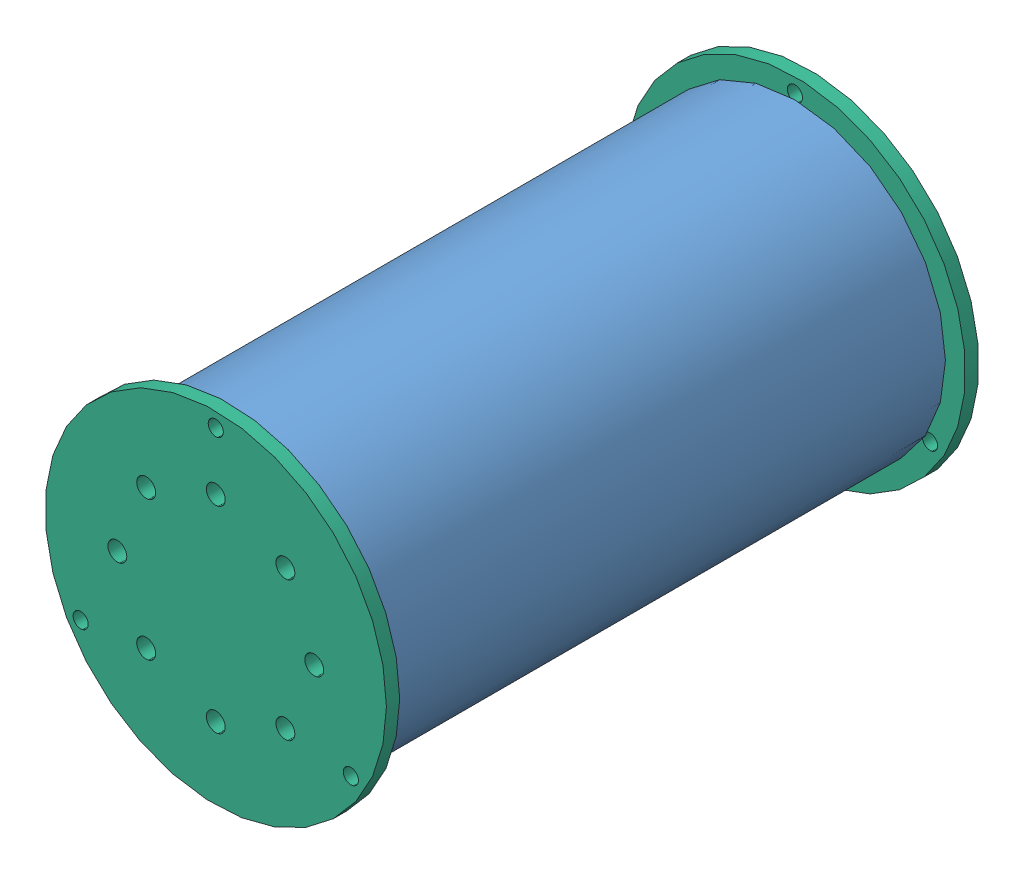
SolidWorks assembly enclosure, configuration Default. Lengths in mm.
Overall size (180 180 327.78).
19 component instances, 6 part files, 13 mates.
Components (placement in the parent):
- tube-1: tube [Default] at origin size (158.75 158.75 298.45)
- board-1: board [Default] at origin size (101.6 76.2 3.81)
- connector-1: connector [Default] at (31.7768 -36.068 -5.2832) x (-1 0 0) z (0 -1 0) size (69.85 16.51 23.62)
- receptical-1: receptical [Default] at (-29.8182 -39.624 0.127) x (1 0 0) z (0 1 0) size (69.85 11.94 21.72)
- backplane-1: backplane [Default] at (1.4763 -54.324 122.6722) x (0 0 1) z (-1 0 0) size (290 2 80)
- receptical-6: receptical [Default] at (-29.8182 -39.624 60.127) x (1 0 0) z (0 1 0) size (69.85 11.94 21.72)
- receptical-7: receptical [Default] at (-29.8182 -39.624 120.127) x (1 0 0) z (0 1 0) size (69.85 11.94 21.72)
- receptical-8: receptical [Default] at (-29.8182 -39.624 180.127) x (1 0 0) z (0 1 0) size (69.85 11.94 21.72)
- receptical-9: receptical [Default] at (-29.8182 -39.624 240.127) x (1 0 0) z (0 1 0) size (69.85 11.94 21.72)
- connector-6: connector [Default] at (31.7768 -36.068 54.7168) x (-1 0 0) z (0 -1 0) size (69.85 16.51 23.62)
- connector-7: connector [Default] at (31.7768 -36.068 114.7168) x (-1 0 0) z (0 -1 0) size (69.85 16.51 23.62)
- connector-8: connector [Default] at (31.7768 -36.068 174.7168) x (-1 0 0) z (0 -1 0) size (69.85 16.51 23.62)
- connector-9: connector [Default] at (31.7768 -36.068 234.7168) x (-1 0 0) z (0 -1 0) size (69.85 16.51 23.62)
- board-6: board [Default] at (0 0 60) size (101.6 76.2 3.81)
- board-7: board [Default] at (0 0 120) size (101.6 76.2 3.81)
- board-8: board [Default] at (0 0 180) size (101.6 76.2 3.81)
- board-9: board [Default] at (0 0 240) size (101.6 76.2 3.81)
- cap-1: cap [Default] at (0 0 283.45) x (0 0 1) z (-1 0 0) size (22 180 180)
- cap-2: cap [Default] at (0 0 15) x (0 0 -1) z (1 0 0) size (22 180 180)
Mates (geometry in assembly coordinates):
- Coincident1: coincident anti-aligned: plane of board-1 through (0 0 0) normal (0 0 -1); plane of connector-1 through (36.7298 -24.257 0) normal (0 0 1)
- Coincident2: coincident anti-aligned: plane of board-1 through (-50.8 -38.1 3.81) normal (0 -1 0); plane of connector-1 through (36.7298 -38.1 0) normal (0 1 0)
- Coincident3: coincident anti-aligned: plane of connector-1 through (31.7768 -39.624 -5.2832) normal (0 -1 0); plane of receptical-1 through (-29.8182 -39.624 0.127) normal (0 1 0)
- Coincident4: coincident anti-aligned: plane of connector-1 through (27.6493 -47.879 -11.811) normal (0 0 1); plane of receptical-1 through (-33.9457 -52.324 -11.811) normal (0 0 -1)
- Coincident5: coincident: line of connector-1 through (-33.9457 -47.879 2.0066) axis (0 0 -1); plane of receptical-1 through (-33.9457 -39.624 0.127) normal (-1 0 0)
- Coincident6: coincident anti-aligned: plane of receptical-1 through (6.6943 -52.324 -11.811) normal (0 -1 0); plane of backplane-1 through (1.4763 -52.324 122.6722) normal (0 1 0)
- Parallel2: parallel anti-aligned: line of connector-1 through (-33.9457 -47.879 -12.573) axis (1 0 0); line of backplane-1 through (41.4763 -52.324 -22.3278) axis (-1 0 0)
- Coincident12: coincident anti-aligned: plane of tube-1 through (0 0 298.45) normal (0 0 1); plane of cap-1 through (0 76.2 298.45) normal (0 0 -1)
- Concentric3: concentric aligned: cylinder of tube-1 through (0 0 0) axis (0 0 1) radius 76.2; cylinder of cap-1 through (0 0 305.45) axis (0 0 1) radius 76.2
- Coincident13: coincident anti-aligned: plane of tube-1 through (0 0 0) normal (0 0 -1); plane of cap-2 through (0 76.2 0) normal (0 0 1)
- Concentric4: concentric anti-aligned: cylinder of tube-1 through (0 0 0) axis (0 0 1) radius 76.2; cylinder of cap-2 through (0 0 -7) axis (0 0 -1) radius 76.2
- Concentric5: concentric aligned: cylinder of cap-1 through (0 82.2773 308.45) axis (0 0 -1) radius 4; cylinder of ? through (0 82.2773 305.45) axis (0 0 -1) radius 4
- Coincident14: coincident aligned: plane of cap-1 through (0 90 305.45) normal (0 0 1); circle of ?
